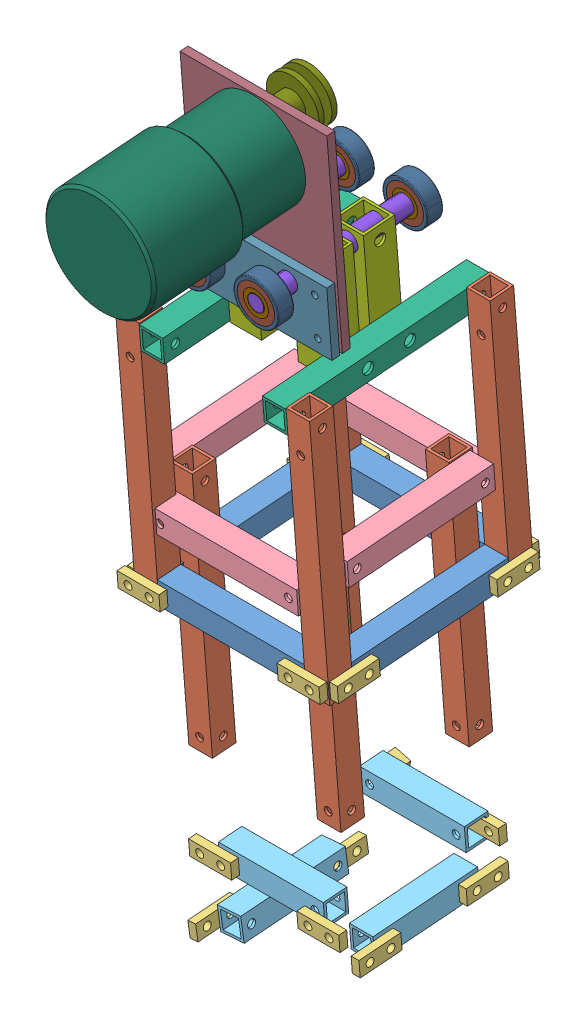
SolidWorks assembly 真.上下可動部分, configuration ﾃﾞﾌｫﾙﾄ. Lengths in mm.
Overall size (80.5 307.91 133.52).
92 component instances, 16 part files, 174 mates.
Components (placement in the parent):
- 三段目固定具-1: 三段目固定具 [ﾃﾞﾌｫﾙﾄ] at (-34.1239 -152.2869 -36.7001) x (0 0.996917 0.078459) z (0 -0.078459 0.996917) size (9 9 60)
- 三段目固定具-2: 三段目固定具 [ﾃﾞﾌｫﾙﾄ] at (-33.6239 -157.3475 27.6011) x (0 -0.996917 -0.078459) z (1 0 0) size (9 9 60)
- 三段目固定具-3: 三段目固定具 [ﾃﾞﾌｫﾙﾄ] at (-29.6239 -151.9338 -41.1862) x (0 -0.996917 -0.078459) z (1 0 0) size (9 9 60)
- 三段目固定具-4: 三段目固定具 [ﾃﾞﾌｫﾙﾄ] at (30.8761 -152.2869 -36.7001) x (0 -0.996917 -0.078459) z (0 -0.078459 0.996917) size (9 9 60)
- スライド縦-1: スライド縦 [ﾃﾞﾌｫﾙﾄ] at (30.8761 -64.6342 34.8978) x (1 0 0) z (0 -0.996917 -0.078459) size (9 9 98)
- スライド縦-2: スライド縦 [ﾃﾞﾌｫﾙﾄ] at (30.8761 -59.2205 -33.8895) x (1 0 0) z (0 -0.996917 -0.078459) size (9 9 98)
- 固定板-1: 固定板 [ﾃﾞﾌｫﾙﾄ] at (35.3761 -152.2476 -37.1986) x (0 0.078459 -0.996917) z (1 0 0) size (16 6 3)
- 固定板-2: 固定板 [ﾃﾞﾌｫﾙﾄ] at (35.3761 -157.0337 23.6134) x (0 0.078459 -0.996917) z (1 0 0) size (16 6 3)
- 固定板-3: 固定板 [ﾃﾞﾌｫﾙﾄ] at (26.8761 -151.3454 -48.6631) x (1 0 0) z (0 -0.078459 0.996917) size (16 6 3)
- 固定板-4: 固定板 [ﾃﾞﾌｫﾙﾄ] at (-30.1239 -151.3454 -48.6631) x (1 0 0) z (0 -0.078459 0.996917) size (16 6 3)
- 固定板-5: 固定板 [ﾃﾞﾌｫﾙﾄ] at (-38.6239 -152.2476 -37.1986) x (0 -0.078459 0.996917) z (-1 0 0) size (16 6 3)
- 固定板-6: 固定板 [ﾃﾞﾌｫﾙﾄ] at (-38.6239 -157.0337 23.6134) x (0 -0.078459 0.996917) z (-1 0 0) size (16 6 3)
- 固定板-7: 固定板 [ﾃﾞﾌｫﾙﾄ] at (26.8761 -157.7006 32.0872) x (1 0 0) z (0 -0.078459 0.996917) size (16 6 3)
- 固定板-8: 固定板 [ﾃﾞﾌｫﾙﾄ] at (-34.1239 -157.7006 32.0872) x (1 0 0) z (0 -0.078459 0.996917) size (16 6 3)
- スライド縦-3: スライド縦 [ﾃﾞﾌｫﾙﾄ] at (-34.1239 -64.6342 34.8978) x (1 0 0) z (0 -0.996917 -0.078459) size (9 9 98)
- スライド縦-4: スライド縦 [ﾃﾞﾌｫﾙﾄ] at (-34.1239 -59.2205 -33.8895) x (1 0 0) z (0 -0.996917 -0.078459) size (9 9 98)
- 三段目固定具ver2-9: 三段目固定具ver2 [ﾃﾞﾌｫﾙﾄ] at (-37.1239 -119.4596 -32.1103) x (0 -0.996917 -0.078459) z (0 -0.078459 0.996917) size (9 9 56)
- スライド縦-9: スライド縦 [ﾃﾞﾌｫﾙﾄ] at (20.8761 -118.5942 20.6201) x (-1 0 0) z (0 -0.996917 -0.078459) size (9 9 98)
- スライド縦-10: スライド縦 [ﾃﾞﾌｫﾙﾄ] at (20.8761 -114.7497 -28.2288) x (-1 0 0) z (0 -0.996917 -0.078459) size (9 9 98)
- スライド縦-12: スライド縦 [ﾃﾞﾌｫﾙﾄ] at (-28.1239 -118.5942 20.6201) x (-1 0 0) z (0 -0.996917 -0.078459) size (9 9 98)
- 三段目固定具ver2-1: 三段目固定具ver2 [ﾃﾞﾌｫﾙﾄ] at (29.8761 -119.4596 -32.1103) x (0 -0.996917 -0.078459) z (0 -0.078459 0.996917) size (9 9 56)
- 三段目固定具ver2-10: 三段目固定具ver2 [ﾃﾞﾌｫﾙﾄ] at (24.3761 -128.0004 -38.2995) x (0 -0.996917 -0.078459) z (-1 0 0) size (9 9 56)
- 三段目固定具ver2-8: 三段目固定具ver2 [ﾃﾞﾌｫﾙﾄ] at (24.3761 -133.2571 28.4939) x (0 -0.996917 -0.078459) z (-1 0 0) size (9 9 56)
- 二段目固定具-7: 二段目固定具 [ﾃﾞﾌｫﾙﾄ] at (20.8761 -258.4916 -35.0277) x (0 -0.996917 -0.078459) z (0 -0.078459 0.996917) size (9 9 40)
- 二段目固定具-8: 二段目固定具 [ﾃﾞﾌｫﾙﾄ] at (-30.7132 -278.7592 -36.5223) x (0.072926 -0.994263 -0.07825) z (0 -0.078459 0.996917) size (9 9 40)
- 二段目固定具-9: 二段目固定具 [ﾃﾞﾌｫﾙﾄ] at (-20.9396 -248.6666 -40.7914) x (0 -0.996917 -0.078459) z (1 0 0) size (9 9 40)
- 二段目固定具-10: 二段目固定具 [ﾃﾞﾌｫﾙﾄ] at (-23.6239 -249.4956 10.3179) x (0 -0.996917 -0.078459) z (1 0 0) size (9 9 40)
- 固定板-17: 固定板 [ﾃﾞﾌｫﾙﾄ] at (-35.2012 -282.2639 3.8271) x (0 -0.078459 0.996917) z (-0.997337 -0.072701 -0.005722) size (16 6 3)
- 固定板-18: 固定板 [ﾃﾞﾌｫﾙﾄ] at (25.3761 -258.4523 -35.5261) x (0 -0.078459 0.996917) z (1 0 0) size (16 6 3)
- 固定板-19: 固定板 [ﾃﾞﾌｫﾙﾄ] at (16.8761 -248.5778 -46.2845) x (1 0 0) z (0 -0.078459 0.996917) size (16 6 3)
- 固定板-20: 固定板 [ﾃﾞﾌｫﾙﾄ] at (16.8761 -253.3638 14.5274) x (1 0 0) z (0 -0.078459 0.996917) size (16 6 3)
- 固定板-21: 固定板 [ﾃﾞﾌｫﾙﾄ] at (28.3761 -261.6692 5.3475) x (0 -0.078459 0.996917) z (-1 0 0) size (16 6 3)
- 固定板-22: 固定板 [ﾃﾞﾌｫﾙﾄ] at (-26.9004 -278.442 -36.9989) x (0 -0.078459 0.996917) z (-0.997337 -0.072701 -0.005722) size (16 6 3)
- 固定板-23: 固定板 [ﾃﾞﾌｫﾙﾄ] at (-18.559 -251.9065 -48.5695) x (0.279856 0.957082 0.075324) z (0 -0.078459 0.996917) size (16 6 3)
- 固定板-24: 固定板 [ﾃﾞﾌｫﾙﾄ] at (-24.1239 -249.8486 14.8041) x (1 0 0) z (0 -0.078459 0.996917) size (16 6 3)
- アームセット接続1-1: アームセット接続1 [ﾃﾞﾌｫﾙﾄ] at (21.8761 -69.9718 38.9916) x (0 0.996917 0.078459) z (0 0.078459 -0.996917) size (9 9 78)
- アームセット接続1-2: アームセット接続1 [ﾃﾞﾌｫﾙﾄ] at (-25.1239 -63.852 -38.7679) x (0 -0.996917 -0.078459) z (0 -0.078459 0.996917) size (9 9 78)
- アームベアリング接続-1: アームベアリング接続 [ﾃﾞﾌｫﾙﾄ] at (-14.6239 -71.2688 -8.2558) x (0 0.078459 -0.996917) z (0 0.996917 0.078459) size (12 12 40)
- アームベアリング接続-2: アームベアリング接続 [ﾃﾞﾌｫﾙﾄ] at (-14.6239 -72.5242 7.6949) x (0 0.078459 -0.996917) z (0 0.996917 0.078459) size (12 12 40)
- アームベアリング接続-3: アームベアリング接続 [ﾃﾞﾌｫﾙﾄ] at (11.3761 -72.5242 7.6949) x (0 0.078459 -0.996917) z (0 0.996917 0.078459) size (12 12 40)
- アームベアリング接続-4: アームベアリング接続 [ﾃﾞﾌｫﾙﾄ] at (11.3761 -71.2688 -8.2558) x (0 0.078459 -0.996917) z (0 0.996917 0.078459) size (12 12 40)
- ベアリング軸-1: ベアリング軸 [ﾃﾞﾌｫﾙﾄ] at (-14.6239 -34.6899 -26.9435) x (-0.850625 0.524152 0.041252) z (0 -0.078459 0.996917) size (7 7 63)
- ベアリング軸-2: ベアリング軸 [ﾃﾞﾌｫﾙﾄ] at (11.3761 -34.6899 -26.9435) x (0.999989 -0.004702 -0.00037) z (0 -0.078459 0.996917) size (7 7 63)
- 606ZZ-1: 606ZZ [Default] at (-14.6239 -39.162 29.8808) x (0 -0.078459 0.996917) z (-0.697769 0.714114 0.056202) size (6 17 17)
  - _606ZZ_Inner_ring_2-1: _606ZZ_Inner_ring_2 [Default] at origin size (6 9.52 9.52)
  - _606ZZ_Outer_ring_4-1: _606ZZ_Outer_ring_4 [Default] at origin size (6 17 17)
  - _606ZZ_Shield_6-1: _606ZZ_Shield_6 [Default] x (-1 0 0) z (0 0 1) size (0.1 14.18 14.18)
  - _606ZZ_Shield_6-2: _606ZZ_Shield_6 [Default] at (6 0 0) size (0.1 14.18 14.18)
  - _606ZZ_Ball_9-1: _606ZZ_Ball_9 [Default] at (3 5.75 0) x (-1 0 0) z (0 0 1) size (3.26 3.26 3.26)
  - _606ZZ_Ball_9-2: _606ZZ_Ball_9 [Default] at (3 2.875 4.9796) x (-1 0 0) z (0 0 1) size (3.26 3.26 3.26)
  - _606ZZ_Ball_9-3: _606ZZ_Ball_9 [Default] at (3 -2.875 4.9796) x (-1 0 0) z (0 0 1) size (3.26 3.26 3.26)
  - _606ZZ_Ball_9-4: _606ZZ_Ball_9 [Default] at (3 -5.75 0) x (-1 0 0) z (0 0 1) size (3.26 3.26 3.26)
  - _606ZZ_Ball_9-5: _606ZZ_Ball_9 [Default] at (3 -2.875 -4.9796) x (-1 0 0) z (0 0 1) size (3.26 3.26 3.26)
  - _606ZZ_Ball_9-6: _606ZZ_Ball_9 [Default] at (3 2.875 -4.9796) x (-1 0 0) z (0 0 1) size (3.26 3.26 3.26)
- 606ZZ-2: 606ZZ [Default] at (-14.6239 -35.1606 -20.962) x (0 0.078459 -0.996917) z (0.998416 0.056094 0.004415) size (6 17 17)
  - _606ZZ_Inner_ring_2-1: _606ZZ_Inner_ring_2 [Default] at origin size (6 9.52 9.52)
  - _606ZZ_Outer_ring_4-1: _606ZZ_Outer_ring_4 [Default] at origin size (6 17 17)
  - _606ZZ_Shield_6-1: _606ZZ_Shield_6 [Default] x (-1 0 0) z (0 0 1) size (0.1 14.18 14.18)
  - _606ZZ_Shield_6-2: _606ZZ_Shield_6 [Default] at (6 0 0) size (0.1 14.18 14.18)
  - _606ZZ_Ball_9-1: _606ZZ_Ball_9 [Default] at (3 5.75 0) x (-1 0 0) z (0 0 1) size (3.26 3.26 3.26)
  - _606ZZ_Ball_9-2: _606ZZ_Ball_9 [Default] at (3 2.875 4.9796) x (-1 0 0) z (0 0 1) size (3.26 3.26 3.26)
  - _606ZZ_Ball_9-3: _606ZZ_Ball_9 [Default] at (3 -2.875 4.9796) x (-1 0 0) z (0 0 1) size (3.26 3.26 3.26)
  - _606ZZ_Ball_9-4: _606ZZ_Ball_9 [Default] at (3 -5.75 0) x (-1 0 0) z (0 0 1) size (3.26 3.26 3.26)
  - _606ZZ_Ball_9-5: _606ZZ_Ball_9 [Default] at (3 -2.875 -4.9796) x (-1 0 0) z (0 0 1) size (3.26 3.26 3.26)
  - _606ZZ_Ball_9-6: _606ZZ_Ball_9 [Default] at (3 2.875 -4.9796) x (-1 0 0) z (0 0 1) size (3.26 3.26 3.26)
- 606ZZ-3: 606ZZ [Default] at (11.3761 -35.1606 -20.962) x (0 0.078459 -0.996917) z (-0.972669 -0.231481 -0.018218) size (6 17 17)
  - _606ZZ_Inner_ring_2-1: _606ZZ_Inner_ring_2 [Default] at origin size (6 9.52 9.52)
  - _606ZZ_Outer_ring_4-1: _606ZZ_Outer_ring_4 [Default] at origin size (6 17 17)
  - _606ZZ_Shield_6-1: _606ZZ_Shield_6 [Default] x (-1 0 0) z (0 0 1) size (0.1 14.18 14.18)
  - _606ZZ_Shield_6-2: _606ZZ_Shield_6 [Default] at (6 0 0) size (0.1 14.18 14.18)
  - _606ZZ_Ball_9-1: _606ZZ_Ball_9 [Default] at (3 5.75 0) x (-1 0 0) z (0 0 1) size (3.26 3.26 3.26)
  - _606ZZ_Ball_9-2: _606ZZ_Ball_9 [Default] at (3 2.875 4.9796) x (-1 0 0) z (0 0 1) size (3.26 3.26 3.26)
  - _606ZZ_Ball_9-3: _606ZZ_Ball_9 [Default] at (3 -2.875 4.9796) x (-1 0 0) z (0 0 1) size (3.26 3.26 3.26)
  - _606ZZ_Ball_9-4: _606ZZ_Ball_9 [Default] at (3 -5.75 0) x (-1 0 0) z (0 0 1) size (3.26 3.26 3.26)
  - _606ZZ_Ball_9-5: _606ZZ_Ball_9 [Default] at (3 -2.875 -4.9796) x (-1 0 0) z (0 0 1) size (3.26 3.26 3.26)
  - _606ZZ_Ball_9-6: _606ZZ_Ball_9 [Default] at (3 2.875 -4.9796) x (-1 0 0) z (0 0 1) size (3.26 3.26 3.26)
- 606ZZ-4: 606ZZ [Default] at (11.3761 -39.162 29.8808) x (0 -0.078459 0.996917) z (-0.999321 -0.036741 -0.002892) size (6 17 17)
  - _606ZZ_Inner_ring_2-1: _606ZZ_Inner_ring_2 [Default] at origin size (6 9.52 9.52)
  - _606ZZ_Outer_ring_4-1: _606ZZ_Outer_ring_4 [Default] at origin size (6 17 17)
  - _606ZZ_Shield_6-1: _606ZZ_Shield_6 [Default] x (-1 0 0) z (0 0 1) size (0.1 14.18 14.18)
  - _606ZZ_Shield_6-2: _606ZZ_Shield_6 [Default] at (6 0 0) size (0.1 14.18 14.18)
  - _606ZZ_Ball_9-1: _606ZZ_Ball_9 [Default] at (3 5.75 0) x (-1 0 0) z (0 0 1) size (3.26 3.26 3.26)
  - _606ZZ_Ball_9-2: _606ZZ_Ball_9 [Default] at (3 2.875 4.9796) x (-1 0 0) z (0 0 1) size (3.26 3.26 3.26)
  - _606ZZ_Ball_9-3: _606ZZ_Ball_9 [Default] at (3 -2.875 4.9796) x (-1 0 0) z (0 0 1) size (3.26 3.26 3.26)
  - _606ZZ_Ball_9-4: _606ZZ_Ball_9 [Default] at (3 -5.75 0) x (-1 0 0) z (0 0 1) size (3.26 3.26 3.26)
  - _606ZZ_Ball_9-5: _606ZZ_Ball_9 [Default] at (3 -2.875 -4.9796) x (-1 0 0) z (0 0 1) size (3.26 3.26 3.26)
  - _606ZZ_Ball_9-6: _606ZZ_Ball_9 [Default] at (3 2.875 -4.9796) x (-1 0 0) z (0 0 1) size (3.26 3.26 3.26)
- マウント&ベルト掴み部分-1: マウント&ベルト掴み部分 [ﾃﾞﾌｫﾙﾄ] at (-1.6239 -45.0813 15.8732) x (1 0 0) z (0 -0.078459 0.996917) size (56 75 3)
- ベルト掴み部分-4: ベルト掴み部分 [ﾃﾞﾌｫﾙﾄ] at (-1.6239 -45.3951 19.8609) x (1 0 0) z (0 -0.078459 0.996917) size (56 25 3)
- ツカサDCモーター-1: ツカサDCモーター [ﾃﾞﾌｫﾙﾄ] at (-1.8205 -6.6947 82.5907) x (-0.999605 0.028005 0.002204) z (0 0.078459 -0.996917) size (42 42 81.5)
- ワイヤー巻取り-1: ワイヤー巻取り [ﾃﾞﾌｫﾙﾄ] at (-1.6239 5.7338 13.8539) x (-0.873289 -0.485701 -0.038226) z (0 0.078459 -0.996917) size (20 20 12)
- スライド縦-17: スライド縦 [ﾃﾞﾌｫﾙﾄ] at (-28.1239 -114.7497 -28.2288) x (1 0 0) z (0 -0.996917 -0.078459) size (9 9 98)
Mates (geometry in assembly coordinates):
- 同心円1: concentric: cylinder of スライド縦-2 through (76.3761 -151.9338 -41.1862) axis (-1 0 0) radius 1.5; cylinder of 固定板-1 through (35.3761 -151.9338 -41.1862) axis (1 0 0) radius 1.5
- 一致1: coincident: plane of スライド縦-2 through (35.3761 -157.2715 -37.0924) normal (1 0 0); plane of 固定板-1 through (35.3761 -152.2476 -37.1986) normal (-1 0 0)
- 平行1: parallel: line of スライド縦-2 through (35.3761 -156.5653 -46.0646) axis (0 -0.078459 0.996917); line of 固定板-1 through (35.3761 -155.8661 -29.4586) axis (0 0.078459 -0.996917)
- 同心円2: concentric: cylinder of 三段目固定具-4 through (-20.6239 -152.5615 -33.2109) axis (1 0 0) radius 1.5; cylinder of 固定板-1 through (35.3761 -152.5615 -33.2109) axis (1 0 0) radius 1.5
- 一致3: coincident: plane of 三段目固定具-4 through (35.3761 -152.5083 23.468) normal (1 0 0); plane of 固定板-1 through (35.3761 -152.2476 -37.1986) normal (-1 0 0)
- 一致4: coincident: plane of 三段目固定具-4 through (30.8761 -152.2869 -36.7001) normal (0 0.078459 -0.996917); plane of スライド縦-2 through (26.3761 -157.2715 -37.0924) normal (0 -0.078459 0.996917)
- 同心円3: concentric: cylinder of 三段目固定具-4 through (-20.6239 -156.7198 19.6257) axis (1 0 0) radius 1.5; cylinder of 固定板-2 through (35.3761 -156.7198 19.6257) axis (1 0 0) radius 1.5
- 一致5: coincident: plane of 三段目固定具-4 through (35.3761 -152.5083 23.468) normal (1 0 0); plane of 固定板-2 through (35.3761 -157.0337 23.6134) normal (-1 0 0)
- 平行2: parallel: line of 三段目固定具-4 through (35.3761 -161.4806 22.7619) axis (0 0.078459 -0.996917); plane of 固定板-2 through (38.3761 -160.6521 31.3534) normal (0 -0.996917 -0.078459)
- 同心円4: concentric: cylinder of スライド縦-1 through (76.3761 -157.3475 27.6011) axis (-1 0 0) radius 1.5; cylinder of 固定板-2 through (35.3761 -157.3475 27.6011) axis (1 0 0) radius 1.5
- 一致7: coincident: plane of スライド縦-1 through (35.3761 -162.6851 31.6949) normal (1 0 0); plane of 固定板-2 through (35.3761 -157.0337 23.6134) normal (-1 0 0)
- 一致8: coincident: plane of 三段目固定具-4 through (30.8761 -156.9944 23.1149) normal (0 -0.078459 0.996917); plane of スライド縦-1 through (26.3761 -161.979 22.7227) normal (0 0.078459 -0.996917)
- 同心円5: concentric: cylinder of スライド縦-1 through (30.8761 -149.3368 -74.1842) axis (0 -0.078459 0.996917) radius 1.5; cylinder of 固定板-7 through (30.8761 -157.7006 32.0872) axis (0 -0.078459 0.996917) radius 1.5
- 一致9: coincident: plane of スライド縦-1 through (26.3761 -162.6851 31.6949) normal (0 -0.078459 0.996917); plane of 固定板-7 through (26.8761 -157.7006 32.0872) normal (0 0.078459 -0.996917)
- 平行3: parallel: line of スライド縦-1 through (35.3761 -162.6851 31.6949) axis (0 0.996917 0.078459); plane of 固定板-7 through (34.8761 -154.9452 35.3133) normal (1 0 0)
- 同心円6: concentric: cylinder of 三段目固定具-2 through (22.8761 -161.3881 78.9423) axis (0 0.078459 -0.996917) radius 1.5; cylinder of 固定板-7 through (22.8761 -157.7006 32.0872) axis (0 -0.078459 0.996917) radius 1.5
- 一致11: coincident: plane of 三段目固定具-2 through (26.3761 -153.2144 32.4403) normal (0 -0.078459 0.996917); plane of 固定板-7 through (26.8761 -157.7006 32.0872) normal (0 0.078459 -0.996917)
- 一致12: coincident: plane of 三段目固定具-2 through (26.3761 -157.3475 27.6011) normal (1 0 0); plane of スライド縦-1 through (26.3761 -162.6851 31.6949) normal (-1 0 0)
- 同心円7: concentric: cylinder of 三段目固定具-2 through (-30.1239 -161.3881 78.9423) axis (0 0.078459 -0.996917) radius 1.5; cylinder of 固定板-8 through (-30.1239 -157.7006 32.0872) axis (0 -0.078459 0.996917) radius 1.5
- 一致13: coincident: plane of 三段目固定具-2 through (26.3761 -153.2144 32.4403) normal (0 -0.078459 0.996917); plane of 固定板-8 through (-34.1239 -157.7006 32.0872) normal (0 0.078459 -0.996917)
- 平行4: parallel: line of 三段目固定具-2 through (26.3761 -153.2144 32.4403) axis (-1 0 0); line of 固定板-8 through (-26.1239 -154.7098 32.3226) axis (-1 0 0)
- 同心円8: concentric: cylinder of 固定板-8 through (-38.1239 -157.7006 32.0872) axis (0 -0.078459 0.996917) radius 1.5; cylinder of スライド縦-3 through (-34.1239 -149.3368 -74.1842) axis (0 -0.078459 0.996917) radius 1.5
- 一致15: coincident: plane of 固定板-8 through (-34.1239 -157.7006 32.0872) normal (0 0.078459 -0.996917); plane of スライド縦-3 through (-38.6239 -162.6851 31.6949) normal (0 -0.078459 0.996917)
- 一致16: coincident: plane of 固定板-8 through (-42.1239 -154.9452 35.3133) normal (-1 0 0); line of スライド縦-3 through (-38.6239 -162.6851 31.6949) axis (0 0.996917 0.078459)
- 同心円9: concentric: cylinder of 固定板-6 through (-38.6239 -157.3475 27.6011) axis (-1 0 0) radius 1.5; cylinder of スライド縦-3 through (11.3761 -157.3475 27.6011) axis (-1 0 0) radius 1.5
- 一致17: coincident: plane of 固定板-6 through (-38.6239 -157.0337 23.6134) normal (1 0 0); plane of スライド縦-3 through (-38.6239 -162.6851 31.6949) normal (-1 0 0)
- 平行5: parallel: line of 固定板-6 through (-38.6239 -159.3967 15.4027) axis (0 -0.078459 0.996917); line of スライド縦-3 through (-38.6239 -162.6851 31.6949) axis (0 0.078459 -0.996917)
- 同心円10: concentric: cylinder of 三段目固定具-1 through (17.3761 -156.7198 19.6257) axis (-1 0 0) radius 1.5; cylinder of 固定板-6 through (-38.6239 -156.7198 19.6257) axis (-1 0 0) radius 1.5
- 一致19: coincident: plane of 三段目固定具-1 through (-38.6239 -161.4806 22.7619) normal (-1 0 0); plane of 固定板-6 through (-38.6239 -157.0337 23.6134) normal (1 0 0)
- 一致20: coincident: plane of 三段目固定具-1 through (-34.1239 -156.9944 23.1149) normal (0 -0.078459 0.996917); plane of スライド縦-3 through (-38.6239 -161.979 22.7227) normal (0 0.078459 -0.996917)
- 同心円11: concentric: cylinder of 三段目固定具-1 through (17.3761 -152.5615 -33.2109) axis (-1 0 0) radius 1.5; cylinder of 固定板-5 through (-38.6239 -152.5615 -33.2109) axis (-1 0 0) radius 1.5
- 一致21: coincident: plane of 三段目固定具-1 through (-38.6239 -161.4806 22.7619) normal (-1 0 0); plane of 固定板-5 through (-38.6239 -152.2476 -37.1986) normal (1 0 0)
- 平行7: parallel: line of 三段目固定具-1 through (-38.6239 -152.5083 23.468) axis (0 0.078459 -0.996917); line of 固定板-5 through (-38.6239 -149.8846 -28.9878) axis (0 0.078459 -0.996917)
- 同心円12: concentric: cylinder of 固定板-5 through (-38.6239 -151.9338 -41.1862) axis (-1 0 0) radius 1.5; cylinder of スライド縦-4 through (11.3761 -151.9338 -41.1862) axis (-1 0 0) radius 1.5
- 一致24: coincident: plane of 三段目固定具-1 through (-34.1239 -152.2869 -36.7001) normal (0 0.078459 -0.996917); plane of スライド縦-4 through (-38.6239 -157.2715 -37.0924) normal (0 -0.078459 0.996917)
- 一致25: coincident: plane of 固定板-5 through (-38.6239 -152.2476 -37.1986) normal (1 0 0); plane of スライド縦-4 through (-38.6239 -157.2715 -37.0924) normal (-1 0 0)
- 同心円13: concentric: cylinder of 固定板-4 through (-34.1239 -151.3454 -48.6631) axis (0 -0.078459 0.996917) radius 1.5; cylinder of スライド縦-4 through (-34.1239 -143.9231 -142.9715) axis (0 -0.078459 0.996917) radius 1.5
- 一致26: coincident: plane of 固定板-4 through (-30.1239 -151.5807 -45.6723) normal (0 -0.078459 0.996917); plane of スライド縦-4 through (-38.6239 -156.5653 -46.0646) normal (0 0.078459 -0.996917)
- 平行8: parallel: plane of 固定板-4 through (-38.1239 -154.5715 -45.9077) normal (0 -0.996917 -0.078459); line of スライド縦-4 through (-38.6239 -156.5653 -46.0646) axis (1 0 0)
- 同心円14: concentric: cylinder of 三段目固定具-3 through (-26.1239 -155.9745 10.155) axis (0 0.078459 -0.996917) radius 1.5; cylinder of 固定板-4 through (-26.1239 -151.3454 -48.6631) axis (0 -0.078459 0.996917) radius 1.5
- 一致28: coincident: plane of 三段目固定具-3 through (-29.6239 -151.9338 -41.1862) normal (-1 0 0); plane of スライド縦-4 through (-29.6239 -157.2715 -37.0924) normal (1 0 0)
- 一致29: coincident: plane of 三段目固定具-3 through (30.3761 -147.0946 -45.3193) normal (0 0.078459 -0.996917); plane of 固定板-4 through (-30.1239 -151.5807 -45.6723) normal (0 -0.078459 0.996917)
- 同心円15: concentric: cylinder of 三段目固定具-3 through (26.8761 -155.9745 10.155) axis (0 0.078459 -0.996917) radius 1.5; cylinder of 固定板-3 through (22.8761 -151.3454 -48.6631) axis (0 -0.078459 0.996917) radius 1.5
- 同心円16: concentric: cylinder of スライド縦-2 through (30.8761 -143.9231 -142.9715) axis (0 -0.078459 0.996917) radius 1.5; cylinder of 固定板-3 through (30.8761 -151.3454 -48.6631) axis (0 -0.078459 0.996917) radius 1.5
- 一致30: coincident: plane of スライド縦-2 through (26.3761 -156.5653 -46.0646) normal (0 0.078459 -0.996917); plane of 固定板-3 through (26.8761 -151.5807 -45.6723) normal (0 -0.078459 0.996917)
- 同心円47: concentric: cylinder of ? through (24.9621 -232.8346 192.6474) axis (0.018068 -0.038641 -0.99909) radius 1.5; cylinder of ? through (25.1609 -233.2597 181.6574) axis (-0.018068 0.038641 0.99909) radius 1.5
- 同心円48: concentric: cylinder of ? through (15.9649 -232.9907 192.4908) axis (0.018068 -0.038641 -0.99909) radius 1.4996; cylinder of ? through (16.1636 -233.4158 181.5008) axis (-0.018068 0.038641 0.99909) radius 1.5
- 一致71: coincident: plane of ? through (12.7396 -237.9725 181.6151) normal (-0.018068 0.038641 0.99909); plane of ? through (29.1597 -233.1903 181.7271) normal (0.018068 -0.038641 -0.99909)
- 一致73: coincident: plane of ? through (12.7396 -237.9725 181.6151) normal (-0.018068 0.038641 0.99909); plane of ? through (12.1648 -233.4852 181.4311) normal (0.018068 -0.038641 -0.99909)
- 同心円49: concentric: cylinder of 三段目固定具ver2-9 through (-84.6239 -80.0388 -25.497) axis (1 0 0) radius 1.5; cylinder of ? through (21.3761 -80.0388 -25.497) axis (-1 0 0) radius 1.5
- 一致76: coincident: plane of 三段目固定具ver2-9 through (-28.6239 -79.3579 23.2065) normal (1 0 0); plane of ? through (-28.6239 -74.7011 -29.5909) normal (-1 0 0)
- 同心円51: concentric: cylinder of ? through (-24.1239 -88.0494 76.2882) axis (0 0.078459 -0.996917) radius 1.5; cylinder of 三段目固定具ver2-10 through (-24.1239 -75.292 -85.8105) axis (0 -0.078459 0.996917) radius 1.5
- 一致77: coincident: plane of ? through (-28.6239 -74.7011 -29.5909) normal (0 0.078459 -0.996917); plane of 三段目固定具ver2-10 through (-27.6239 -75.1996 -29.6301) normal (0 -0.078459 0.996917)
- 垂直3: perpendicular: line of ? through (-19.6239 -74.7011 -29.5909) axis (-1 0 0); line of 三段目固定具ver2-10 through (-27.6239 -84.1718 -30.3362) axis (0 0.996917 0.078459)
- 垂直4: perpendicular: line of 三段目固定具ver2-9 through (-28.6239 -84.2503 -29.3393) axis (0 0.996917 0.078459); plane of ? through (-24.1239 -75.0542 -25.1047) normal (0 0.996917 0.078459)
- 距離7: distance = 2 mm: plane of スライド縦-2 through (26.3761 -157.2715 -37.0924) normal (0 -0.078459 0.996917); plane of 三段目固定具ver2-1 through (29.8761 -119.4596 -32.1103) normal (0 0.078459 -0.996917)
- 同心円67: concentric: cylinder of 二段目固定具-7 through (-12.6239 -258.7662 -31.5385) axis (1 0 0) radius 1.5; cylinder of 固定板-18 through (25.3761 -258.7662 -31.5385) axis (1 0 0) radius 1.5
- 一致113: coincident: plane of 二段目固定具-7 through (25.3761 -257.1438 5.2021) normal (1 0 0); plane of 固定板-18 through (25.3761 -258.4523 -35.5261) normal (-1 0 0)
- 同心円69: concentric: cylinder of ? through (-24.1239 -175.7782 69.3838) axis (0 0.078459 -0.996917) radius 1.5; cylinder of 固定板-23 through (-24.1239 -167.179 -39.8783) axis (0 -0.078459 0.996917) radius 1.5
- 一致116: coincident: plane of ? through (-28.6239 -74.7011 -29.5909) normal (0 0.078459 -0.996917); plane of 固定板-23 through (-20.1239 -167.4144 -36.8876) normal (0 -0.078459 0.996917)
- 同心円71: concentric: cylinder of ? through (21.3761 -167.7675 -32.4014) axis (-1 0 0) radius 1.5; cylinder of 固定板-22 through (-28.6239 -167.7675 -32.4014) axis (-1 0 0) radius 1.5
- 一致118: coincident: plane of ? through (-28.6239 -74.7011 -29.5909) normal (-1 0 0); plane of 固定板-22
- 同心円74: concentric: cylinder of 二段目固定具-8 through (-64.124 -281.4692 -33.2247) axis (0.997337 0.072701 0.005722) radius 1.5; cylinder of 固定板-22 through (-26.9004 -278.7558 -33.0112) axis (-0.997337 -0.072701 -0.005722) radius 1.5
- 一致121: coincident: plane of ? through (-28.6239 -75.4072 -20.6186) normal (0 -0.078459 0.996917); plane of 二段目固定具-8 through (-24.1239 -168.1206 -27.9153) normal (0 0.078459 -0.996917)
- 平行42: parallel: plane of 二段目固定具-7 through (25.3761 -266.1161 4.496) normal (0 -0.996917 -0.078459); plane of 固定板-21 through (25.3761 -264.0322 -2.8632) normal (0 -0.996917 -0.078459)
- 同心円81: concentric: cylinder of 二段目固定具-7 through (-12.6239 -261.3553 1.3598) axis (1 0 0) radius 1.5; cylinder of 固定板-21 through (28.3761 -261.3553 1.3598) axis (-1 0 0) radius 1.5
- 平行45: parallel: plane of 二段目固定具-8 through (-25.897 -286.0445 3.028) normal (0.072926 -0.994263 -0.07825); plane of 固定板-17 through (-37.9745 -284.8371 -4.4001) normal (0.072926 -0.994263 -0.07825)
- 同心円85: concentric: cylinder of 二段目固定具-8 through (-64.124 -284.0584 -0.3265) axis (0.997337 0.072701 0.005722) radius 1.5; cylinder of 固定板-17 through (-35.2012 -281.9501 -0.1605) axis (-0.997337 -0.072701 -0.005722) radius 1.5
- 同心円86: concentric: cylinder of 二段目固定具-9 through (-17.4396 -251.295 -7.3946) axis (0 0.078459 -0.996917) radius 1.5; cylinder of 固定板-23 through (-17.4396 -248.0781 -48.2682) axis (0 -0.078459 0.996917) radius 1.5
- 一致124: coincident: plane of 二段目固定具-9 through (19.0604 -243.8274 -44.9244) normal (0 0.078459 -0.996917); plane of 固定板-23 through (-18.559 -252.1418 -45.5788) normal (0 -0.078459 0.996917)
- 同心円88: concentric: cylinder of 二段目固定具-10 through (-20.1239 -252.1239 43.7147) axis (0 0.078459 -0.996917) radius 1.5; cylinder of 固定板-24 through (-20.1239 -249.8486 14.8041) axis (0 -0.078459 0.996917) radius 1.5
- 一致126: coincident: plane of 二段目固定具-10 through (16.3761 -245.3625 15.1571) normal (0 -0.078459 0.996917); plane of 固定板-24 through (-24.1239 -249.8486 14.8041) normal (0 0.078459 -0.996917)
- 平行48: parallel: plane of 二段目固定具-10 through (16.3761 -253.6286 5.4787) normal (0 -0.996917 -0.078459); plane of 固定板-24 through (-32.1239 -253.0748 17.5594) normal (0 -0.996917 -0.078459)
- 距離8: distance = 2 mm: plane of 三段目固定具ver2-10 through (24.3761 -128.0004 -38.2995) normal (1 0 0); plane of スライド縦-2 through (26.3761 -157.2715 -37.0924) normal (-1 0 0)
- 一致130: coincident: plane of 二段目固定具-8 through (-35.5294 -277.7505 3.6808) normal (-0.997337 -0.072701 -0.005722); plane of 固定板-17 through (-35.2012 -282.2639 3.8271) normal (0.997337 0.072701 0.005722)
- 同心円105: concentric: cylinder of ? through (10.8761 -94.7554 85.7914) axis (0 0.078459 -0.996917) radius 1.5; cylinder of ? through (10.8761 -83.4102 -58.3629) axis (0 -0.078459 0.996917) radius 1.5
- 同心円106: concentric: cylinder of ? through (-14.1239 -94.7554 85.7914) axis (0 0.078459 -0.996917) radius 1.5; cylinder of ? through (-14.1239 -83.4102 -58.3629) axis (0 -0.078459 0.996917) radius 1.5
- 一致143: coincident: plane of ? through (-18.6239 -81.4071 -20.0877) normal (0 0.078459 -0.996917); plane of ? through (-17.6239 -81.9055 -20.1269) normal (0 -0.078459 0.996917)
- 一致144: coincident: plane of ? through (-18.6239 -233.7643 -23.0507) normal (0 -0.078459 0.996917); plane of ? through (-14.1239 -335.0511 -31.0221) normal (0 0.078459 -0.996917)
- 一致145: coincident: plane of ? through (-18.6239 -235.0197 -7.1) normal (0 0.078459 -0.996917); plane of ? through (-14.1239 -336.3065 -15.0714) normal (0 -0.078459 0.996917)
- 同心円107: concentric: cylinder of ? through (31.3761 -336.6595 -10.5853) axis (-1 0 0) radius 1.5; cylinder of ? through (-18.6239 -336.6595 -10.5853) axis (-1 0 0) radius 1.5
- 一致147: coincident: plane of ? through (-18.6239 -235.0197 -7.1) normal (-1 0 0); plane of ? through (-18.6239 -336.3457 -14.573) normal (1 0 0)
- 平行60: parallel: plane of ? through (-14.1239 -341.6441 -10.9776) normal (0 -0.996917 -0.078459); plane of ? through (-21.6239 -338.7088 -22.7837) normal (0 -0.996917 -0.078459)
- 一致149: coincident: plane of ? through (-18.6239 -340.7926 -15.4245) normal (-1 0 0); plane of ? through (-18.6239 -336.3457 -14.573) normal (1 0 0)
- 同心円110: concentric: cylinder of ? through (1.3761 -336.0319 -18.5606) axis (-1 0 0) radius 1.4996; cylinder of ? through (-18.6239 -336.0319 -18.5606) axis (-1 0 0) radius 1.5
- 同心円111: concentric: cylinder of ? through (31.3761 -334.6981 -35.5082) axis (-1 0 0) radius 1.5; cylinder of ? through (-18.6239 -334.6981 -35.5082) axis (-1 0 0) radius 1.5
- 同心円112: concentric: cylinder of ? through (1.3761 -335.3257 -27.5329) axis (-1 0 0) radius 1.5; cylinder of ? through (-18.6239 -335.3257 -27.5329) axis (-1 0 0) radius 1.5
- 一致150: coincident: plane of ? through (-18.6239 -233.0582 -32.0229) normal (-1 0 0); plane of ? through (-18.6239 -335.0119 -31.5206) normal (1 0 0)
- 同心円113: concentric: cylinder of ? through (-14.1239 -342.7087 66.277) axis (0 0.078459 -0.996917) radius 1.5; cylinder of ? through (-14.1239 -334.1096 -42.9851) axis (0 -0.078459 0.996917) radius 1.5
- 一致151: coincident: plane of ? through (-18.6239 -233.0582 -32.0229) normal (0 0.078459 -0.996917); plane of ? through (-10.1239 -334.3432 -39.9942) normal (0 -0.078459 0.996917)
- 同心円114: concentric: cylinder of ? through (10.8761 -342.7087 66.277) axis (0 0.078459 -0.996917) radius 1.5; cylinder of ? through (10.8761 -334.1096 -42.9851) axis (0 -0.078459 0.996917) radius 1.5
- 一致152: coincident: plane of ? through (6.3761 -233.0582 -32.0229) normal (0 0.078459 -0.996917); plane of ? through (6.8761 -334.3442 -39.9943) normal (0 -0.078459 0.996917)
- 同心円115: concentric: cylinder of ? through (-6.1239 -334.1061 -42.9848) axis (0 -0.078459 0.996917) radius 1.5; cylinder of ? through (-6.1239 -335.9107 -20.0557) axis (0 0.078459 -0.996917) radius 1.4996
- 同心円116: concentric: cylinder of ? through (2.8761 -334.108 -42.985) axis (0 -0.078459 0.996917) radius 1.5; cylinder of ? through (2.8761 -335.9125 -20.0559) axis (0 0.078459 -0.996917) radius 1.5
- 一致153: coincident: line of ? through (6.3761 -233.0582 -32.0229) axis (0 -0.996917 -0.078459); plane of ? through (-9.6248 -338.8269 -40.3471) normal (0 0.078459 -0.996917)
- 同心円117: concentric: cylinder of ? through (56.3761 -334.6981 -35.5082) axis (-1 0 0) radius 1.5; cylinder of ? through (18.3761 -334.6981 -35.5082) axis (-1 0 0) radius 1.5
- 同心円118: concentric: cylinder of ? through (56.3761 -336.6595 -10.5853) axis (-1 0 0) radius 1.5; cylinder of ? through (18.3761 -336.6595 -10.5853) axis (-1 0 0) radius 1.5
- 一致154: coincident: plane of ? through (15.3761 -235.0197 -7.1) normal (1 0 0); plane of ? through (15.3761 -336.3457 -14.573) normal (-1 0 0)
- 一致155: coincident: plane of ? through (15.3761 -233.0582 -32.0229) normal (1 0 0); plane of ? through (15.3761 -335.0119 -31.5206) normal (-1 0 0)
- 同心円119: concentric: cylinder of ? through (10.8761 -344.6702 91.2) axis (0 0.078459 -0.996917) radius 1.5; cylinder of ? through (10.8761 -337.0126 -6.0992) axis (0 -0.078459 0.996917) radius 1.5
- 一致156: coincident: plane of ? through (6.3761 -235.7258 1.8723) normal (0 -0.078459 0.996917); plane of ? through (6.8761 -337.0111 -6.0991) normal (0 0.078459 -0.996917)
- 同心円120: concentric: cylinder of ? through (-14.1239 -344.6702 91.2) axis (0 0.078459 -0.996917) radius 1.5; cylinder of ? through (-14.1239 -337.0126 -6.0992) axis (0 -0.078459 0.996917) radius 1.5
- 一致157: coincident: plane of ? through (-18.6239 -235.7258 1.8723) normal (0 -0.078459 0.996917); plane of ? through (-10.1239 -337.0095 -6.0989) normal (0 0.078459 -0.996917)
- 同心円122: concentric: cylinder of ? through (18.3761 -336.0319 -18.5606) axis (-1 0 0) radius 1.5; cylinder of ? through (26.3761 -336.0319 -18.5606) axis (-1 0 0) radius 1.4996
- 同心円123: concentric: cylinder of ? through (18.3761 -335.3258 -27.5329) axis (-1 0 0) radius 1.5; cylinder of ? through (26.3761 -335.3258 -27.5329) axis (-1 0 0) radius 1.5
- 一致158: coincident: plane of ? through (15.3761 -335.0119 -31.5206) normal (-1 0 0); plane of ? through (15.3761 -340.7926 -15.4245) normal (1 0 0)
- 同心円124: concentric: cylinder of ? through (2.8761 -337.0096 -6.0989) axis (0 -0.078459 0.996917) radius 1.5; cylinder of ? through (2.8761 -337.8727 4.8671) axis (0 0.078459 -0.996917) radius 1.4996
- 正接3: tangent: cylinder of ? through (-6.1239 -337.8694 4.8674) axis (0 0.078459 -0.996917) radius 1.5; cylinder of ? through (-6.1239 -337.0063 -6.0987) axis (0 -0.078459 0.996917) radius 1.5
- 一致159: coincident: plane of ? through (-10.1239 -337.0095 -6.0989) normal (0 0.078459 -0.996917); plane of ? through (6.3778 -332.5248 -5.746) normal (0 -0.078459 0.996917)
- 同心円134: concentric: cylinder of スライド縦-2 through (76.3761 -64.2051 -34.2818) axis (-1 0 0) radius 1.5; cylinder of アームセット接続1-1 through (-48.6239 -64.2051 -34.2818) axis (1 0 0) radius 1.65
- 同心円135: concentric: cylinder of スライド縦-1 through (76.3761 -69.6188 34.5055) axis (-1 0 0) radius 1.5; cylinder of アームセット接続1-1 through (-48.6239 -69.6188 34.5055) axis (1 0 0) radius 1.65
- 一致168: coincident: plane of スライド縦-1 through (26.3761 -162.6851 31.6949) normal (-1 0 0); plane of アームセット接続1-1 through (26.3761 -68.3381 -39.121) normal (1 0 0)
- 同心円136: concentric: cylinder of スライド縦-4 through (11.3761 -64.2051 -34.2818) axis (-1 0 0) radius 1.5; cylinder of アームセット接続1-2 through (-95.6239 -64.2051 -34.2818) axis (1 0 0) radius 1.65
- 平行70: parallel: cylinder of スライド縦-3 through (11.3761 -69.6188 34.5055) axis (-1 0 0) radius 1.5; cylinder of アームセット接続1-2 through (-95.6239 -69.6188 34.5055) axis (1 0 0) radius 1.65
- 同心円139: concentric: cylinder of スライド縦-3 through (11.3761 -69.6188 34.5055) axis (-1 0 0) radius 1.5; cylinder of アームセット接続1-2 through (-95.6239 -69.6188 34.5055) axis (1 0 0) radius 1.65
- 一致169: coincident: plane of スライド縦-4 through (-29.6239 -157.2715 -37.0924) normal (1 0 0); plane of アームセット接続1-2 through (-29.6239 -65.4857 39.3447) normal (-1 0 0)
- 同心円140: concentric: cylinder of アームセット接続1-2 through (-95.6239 -66.2843 -7.8635) axis (1 0 0) radius 2.1; cylinder of アームベアリング接続-1 through (26.8761 -66.2843 -7.8635) axis (-1 0 0) radius 2.1
- 同心円141: concentric: cylinder of アームセット接続1-2 through (-95.6239 -67.5396 8.0872) axis (1 0 0) radius 2.1; cylinder of アームベアリング接続-2 through (26.8761 -67.5396 8.0872) axis (-1 0 0) radius 2.1
- 一致170: coincident: plane of アームセット接続1-2 through (-20.6239 -65.4857 39.3447) normal (1 0 0); plane of アームベアリング接続-2 through (-20.6239 -33.1182 16.8147) normal (-1 0 0)
- 一致171: coincident: plane of アームセット接続1-2 through (-20.6239 -65.4857 39.3447) normal (1 0 0); plane of アームベアリング接続-1 through (-20.6239 -31.8629 0.8641) normal (-1 0 0)
- 垂直6: perpendicular: line of アームセット接続1-2 through (-20.6239 -65.4857 39.3447) axis (0 0.078459 -0.996917); line of アームベアリング接続-2 through (-20.6239 -33.1182 16.8147) axis (0 -0.996917 -0.078459)
- 垂直8: perpendicular: line of アームセット接続1-2 through (-20.6239 -65.4857 39.3447) axis (0 0.078459 -0.996917); line of アームベアリング接続-1 through (-20.6239 -31.8629 0.8641) axis (0 -0.996917 -0.078459)
- 同心円142: concentric: cylinder of アームセット接続1-1 through (-48.6239 -66.2843 -7.8635) axis (1 0 0) radius 2.1; cylinder of アームベアリング接続-4 through (52.8761 -66.2843 -7.8635) axis (-1 0 0) radius 2.1
- 一致174: coincident: plane of アームセット接続1-1 through (17.3761 -68.3381 -39.121) normal (-1 0 0); plane of アームベアリング接続-4 through (17.3761 -31.8629 0.8641) normal (1 0 0)
- 一致175: coincident: circle of アームセット接続1-1; cylinder of アームベアリング接続-3 through (52.8761 -67.5396 8.0872) axis (-1 0 0) radius 2.1
- 一致176: coincident: plane of アームセット接続1-1 through (17.3761 -68.3381 -39.121) normal (-1 0 0); plane of アームベアリング接続-3 through (17.3761 -33.1182 16.8147) normal (1 0 0)
- 垂直9: perpendicular: line of アームセット接続1-1 through (17.3761 -59.3659 -38.4149) axis (0 -0.078459 0.996917); line of アームベアリング接続-3 through (17.3761 -33.1182 16.8147) axis (0 -0.996917 -0.078459)
- 垂直10: perpendicular: line of アームセット接続1-1 through (17.3761 -59.3659 -38.4149) axis (0 -0.078459 0.996917); line of アームベアリング接続-4 through (17.3761 -30.9214 -11.0989) axis (0 -0.996917 -0.078459)
- 同心円143: concentric: cylinder of アームベアリング接続-1 through (-14.6239 -33.1207 -46.8818) axis (0 -0.078459 0.996917) radius 3.5; cylinder of ベアリング軸-1 through (-14.6239 -39.6328 35.8623) axis (0 0.078459 -0.996917) radius 3.5
- 同心円144: concentric: cylinder of アームベアリング接続-4 through (11.3761 -33.1207 -46.8818) axis (0 -0.078459 0.996917) radius 3.5; cylinder of ベアリング軸-2 through (11.3761 -39.6328 35.8623) axis (0 0.078459 -0.996917) radius 3.5
- 同心円145: concentric: cylinder of ベアリング軸-1 through (-14.6239 -39.162 29.8808) axis (0 -0.078459 0.996917) radius 3; cylinder of 606ZZ-1/_606ZZ_Inner_ring_2-1 through (-14.6239 -39.6328 35.8623) axis (0 0.078459 -0.996917) radius 3
- 一致179: coincident: plane of ベアリング軸-1 through (-14.6239 -39.162 29.8808) normal (0 -0.078459 0.996917); plane of 606ZZ-1/_606ZZ_Inner_ring_2-1 through (-11.2142 -35.8509 30.1414) normal (0 0.078459 -0.996917)
- 同心円146: concentric: cylinder of ベアリング軸-2 through (11.3761 -39.162 29.8808) axis (0 -0.078459 0.996917) radius 3; cylinder of 606ZZ-4/_606ZZ_Inner_ring_2-1 through (11.3761 -39.6328 35.8623) axis (0 0.078459 -0.996917) radius 3
- 一致180: coincident: plane of ベアリング軸-2 through (11.3761 -39.162 29.8808) normal (0 -0.078459 0.996917); plane of 606ZZ-4/_606ZZ_Inner_ring_2-1 through (11.2007 -34.4199 30.254) normal (0 0.078459 -0.996917)
- 同心円147: concentric: cylinder of ベアリング軸-1 through (-14.6239 -35.1606 -20.962) axis (0 0.078459 -0.996917) radius 3; cylinder of 606ZZ-2/_606ZZ_Inner_ring_2-1 through (-14.6239 -34.6899 -26.9435) axis (0 -0.078459 0.996917) radius 3
- 一致181: coincident: plane of ベアリング軸-1 through (-14.6239 -35.1606 -20.962) normal (0 0.078459 -0.996917); plane of 606ZZ-2/_606ZZ_Inner_ring_2-1 through (-14.8917 -30.4228 -20.5891) normal (0 -0.078459 0.996917)
- 同心円148: concentric: cylinder of ベアリング軸-2 through (11.3761 -35.1606 -20.962) axis (0 0.078459 -0.996917) radius 3; cylinder of 606ZZ-3/_606ZZ_Inner_ring_2-1 through (11.3761 -34.6899 -26.9435) axis (0 -0.078459 0.996917) radius 3
- 一致182: coincident: plane of ベアリング軸-2 through (11.3761 -35.1606 -20.962) normal (0 0.078459 -0.996917); plane of 606ZZ-3/_606ZZ_Inner_ring_2-1 through (12.4814 -39.7762 -21.3252) normal (0 -0.078459 0.996917)
- 同心円156: concentric: cylinder of ベアリング軸-2 through (11.3761 -44.802 31.4431) axis (0 0.078459 -0.996917) radius 3.5; cylinder of ? through (11.3761 -41.389 -11.9228) axis (0 0.078459 -0.996917) radius 3.5
- 同心円159: concentric: cylinder of ベアリング軸-1 through (-14.6239 -44.802 31.4431) axis (0 0.078459 -0.996917) radius 3.5; cylinder of ? through (-14.6239 -41.389 -11.9228) axis (0 0.078459 -0.996917) radius 3.5
- 一致185: coincident: plane of アームベアリング接続-4 through (5.3761 -36.4044 -11.5305) normal (0 0.078459 -0.996917); plane of ? through (-1.6239 -48.3674 -12.472) normal (0 -0.078459 0.996917)
- 一致186: coincident: cylinder of ベアリング軸-2 through (11.3761 -44.802 31.4431) axis (0 0.078459 -0.996917) radius 3.5; circle of ?
- 同心円160: concentric: cylinder of ベアリング軸-1 through (-14.6239 -44.802 31.4431) axis (0 0.078459 -0.996917) radius 3.5; cylinder of ? through (-14.6239 -41.0752 -15.9104) axis (0 0.078459 -0.996917) radius 3.5
- 距離20: distance = 1 mm: plane of ? through (-1.6239 -48.1321 -15.4627) normal (0 0.078459 -0.996917); plane of ? through (-1.6239 -48.0536 -16.4597) normal (0 -0.078459 0.996917)
- 距離22: distance = 13.5 mm: plane of 606ZZ-1/_606ZZ_Inner_ring_2-1 through (-11.2142 -35.8509 30.1414) normal (0 0.078459 -0.996917); plane of アームベアリング接続-2 through (-20.6239 -33.1182 16.8147) normal (0 -0.078459 0.996917)
- 距離23: distance = 13.5 mm: plane of 606ZZ-4/_606ZZ_Inner_ring_2-1 through (11.2007 -34.4199 30.254) normal (0 0.078459 -0.996917); plane of アームベアリング接続-3 through (5.3761 -33.1182 16.8147) normal (0 -0.078459 0.996917)
- 同心円161: concentric: cylinder of ベアリング軸-2 through (11.3761 -39.6328 35.8623) axis (0 0.078459 -0.996917) radius 3.5; cylinder of マウント&ベルト掴み部分-1 through (11.3761 -38.3382 19.4132) axis (0 0.078459 -0.996917) radius 3.5
- 同心円162: concentric: cylinder of ベアリング軸-1 through (-14.6239 -39.6328 35.8623) axis (0 0.078459 -0.996917) radius 3.5; cylinder of マウント&ベルト掴み部分-1 through (-14.6239 -38.3382 19.4132) axis (0 0.078459 -0.996917) radius 3.5
- 一致191: coincident: plane of アームベアリング接続-3 through (5.3761 -33.1182 16.8147) normal (0 -0.078459 0.996917); plane of マウント&ベルト掴み部分-1 through (-1.6239 -45.0813 15.8732) normal (0 0.078459 -0.996917)
- 同心円163: concentric: cylinder of ベアリング軸-2 through (11.3761 -39.6328 35.8623) axis (0 0.078459 -0.996917) radius 3.5; cylinder of ベルト掴み部分-4 through (11.3761 -38.652 23.4009) axis (0 0.078459 -0.996917) radius 3.5
- 同心円164: concentric: cylinder of ベアリング軸-1 through (-14.6239 -39.6328 35.8623) axis (0 0.078459 -0.996917) radius 3.5; cylinder of ベルト掴み部分-4 through (-14.6239 -38.652 23.4009) axis (0 0.078459 -0.996917) radius 3.5
- 距離24: distance = 1 mm: plane of マウント&ベルト掴み部分-1 through (-1.6239 -45.3166 18.864) normal (0 -0.078459 0.996917); plane of ベルト掴み部分-4 through (-1.6239 -45.3951 19.8609) normal (0 0.078459 -0.996917)
- 同心円165: concentric: cylinder of マウント&ベルト掴み部分-1 through (-1.6239 2.1247 59.7121) axis (0 0.078459 -0.996917) radius 6.1; cylinder of ツカサDCモーター-1 through (-1.6239 5.4984 16.8447) axis (0 -0.078459 0.996917) radius 6
- 一致192: coincident: plane of マウント&ベルト掴み部分-1 through (-1.6239 -45.3166 18.864) normal (0 -0.078459 0.996917); plane of ツカサDCモーター-1 through (-1.8205 -1.948 22.2772) normal (0 0.078459 -0.996917)
- 同心円166: concentric: cylinder of ツカサDCモーター-1 through (-1.6239 6.6753 1.8909) axis (0 -0.078459 0.996917) radius 3; cylinder of ワイヤー巻取り-1 through (-1.6239 6.1261 8.8693) axis (0 -0.078459 0.996917) radius 3
- 一致193: coincident: circle of ツカサDCモーター-1; plane of ワイヤー巻取り-1 through (-1.6239 5.7338 13.8539) normal (0 -0.078459 0.996917)
- 同心円167: concentric: cylinder of スライド縦-12 through (-28.1239 -140.5617 121.3069) axis (0 0.078459 -0.996917) radius 1.5; cylinder of 三段目固定具ver2-8 through (-28.1239 -129.2165 -22.8473) axis (0 -0.078459 0.996917) radius 1.5
- 同心円168: concentric: cylinder of スライド縦-9 through (20.8761 -140.5617 121.3069) axis (0 0.078459 -0.996917) radius 1.5; cylinder of 三段目固定具ver2-8 through (20.8761 -129.2165 -22.8473) axis (0 -0.078459 0.996917) radius 1.5
- 一致194: coincident: plane of スライド縦-9 through (25.3761 -216.6451 17.4172) normal (0 -0.078459 0.996917); plane of 三段目固定具ver2-8 through (-31.6239 -128.4179 24.3609) normal (0 0.078459 -0.996917)
- 一致195: coincident: plane of スライド縦-12 through (-23.6239 -216.6451 17.4172) normal (0 -0.078459 0.996917); plane of 三段目固定具ver2-8 through (-31.6239 -128.4179 24.3609) normal (0 0.078459 -0.996917)
- 一致196: coincident: circle of スライド縦-9; cylinder of 三段目固定具ver2-1 through (-21.6239 -123.5787 20.2278) axis (1 0 0) radius 1.5
- 同心円169: concentric: cylinder of スライド縦-10 through (-24.6239 -119.7342 -28.6211) axis (1 0 0) radius 1.5; cylinder of 三段目固定具ver2-1 through (-21.6239 -119.7342 -28.6211) axis (1 0 0) radius 1.5
- 一致197: coincident: plane of スライド縦-10 through (25.3761 -212.0945 -40.404) normal (1 0 0); plane of 三段目固定具ver2-1 through (25.3761 -119.3672 24.0701) normal (-1 0 0)
- 一致198: coincident: plane of スライド縦-9 through (25.3761 -215.939 8.445) normal (1 0 0); plane of 三段目固定具ver2-1 through (25.3761 -119.3672 24.0701) normal (-1 0 0)
- 同心円170: concentric: cylinder of スライド縦-10 through (20.8761 -136.7172 72.458) axis (0 0.078459 -0.996917) radius 1.5; cylinder of 三段目固定具ver2-10 through (20.8761 -123.9597 -89.6408) axis (0 -0.078459 0.996917) radius 1.5
- 同心円171: concentric: cylinder of 三段目固定具ver2-10 through (-28.1239 -123.9597 -89.6408) axis (0 -0.078459 0.996917) radius 1.5; cylinder of スライド縦-17 through (-28.1239 -120.6958 -131.1125) axis (0 -0.078459 0.996917) radius 1.5
- 一致200: coincident: plane of 三段目固定具ver2-10 through (-31.6239 -123.8673 -33.4603) normal (0 -0.078459 0.996917); plane of スライド縦-17 through (-32.6239 -212.0945 -40.404) normal (0 0.078459 -0.996917)
- 同心円172: concentric: cylinder of 三段目固定具ver2-9 through (-88.6239 -119.7342 -28.6211) axis (1 0 0) radius 1.5; cylinder of スライド縦-17 through (17.3761 -119.7342 -28.6211) axis (-1 0 0) radius 1.5
- 同心円173: concentric: cylinder of 三段目固定具ver2-9 through (-88.6239 -123.5787 20.2278) axis (1 0 0) radius 1.5; cylinder of スライド縦-12 through (-73.6239 -123.5787 20.2278) axis (1 0 0) radius 1.5
- 一致201: coincident: plane of 三段目固定具ver2-9 through (-32.6239 -119.3672 24.0701) normal (1 0 0); plane of スライド縦-12 through (-32.6239 -215.939 8.445) normal (-1 0 0)
- 平行71: parallel: line of スライド縦-9 through (25.3761 -118.9472 25.1062) axis (-1 0 0); line of 三段目固定具ver2-8 through (-31.6239 -128.4179 24.3609) axis (1 0 0)
- 平行72: parallel: line of スライド縦-9 through (25.3761 -118.2411 16.134) axis (0 -0.078459 0.996917); line of 三段目固定具ver2-1 through (25.3761 -119.3672 24.0701) axis (0 0.078459 -0.996917)
- 平行73: parallel: line of 三段目固定具ver2-10 through (-31.6239 -123.8673 -33.4603) axis (1 0 0); line of スライド縦-17 through (-32.6239 -114.3966 -32.715) axis (1 0 0)
- 平行74: parallel: line of 三段目固定具ver2-9 through (-32.6239 -119.3672 24.0701) axis (0 0.078459 -0.996917); line of スライド縦-17 through (-32.6239 -115.1027 -23.7427) axis (0 0.078459 -0.996917)
